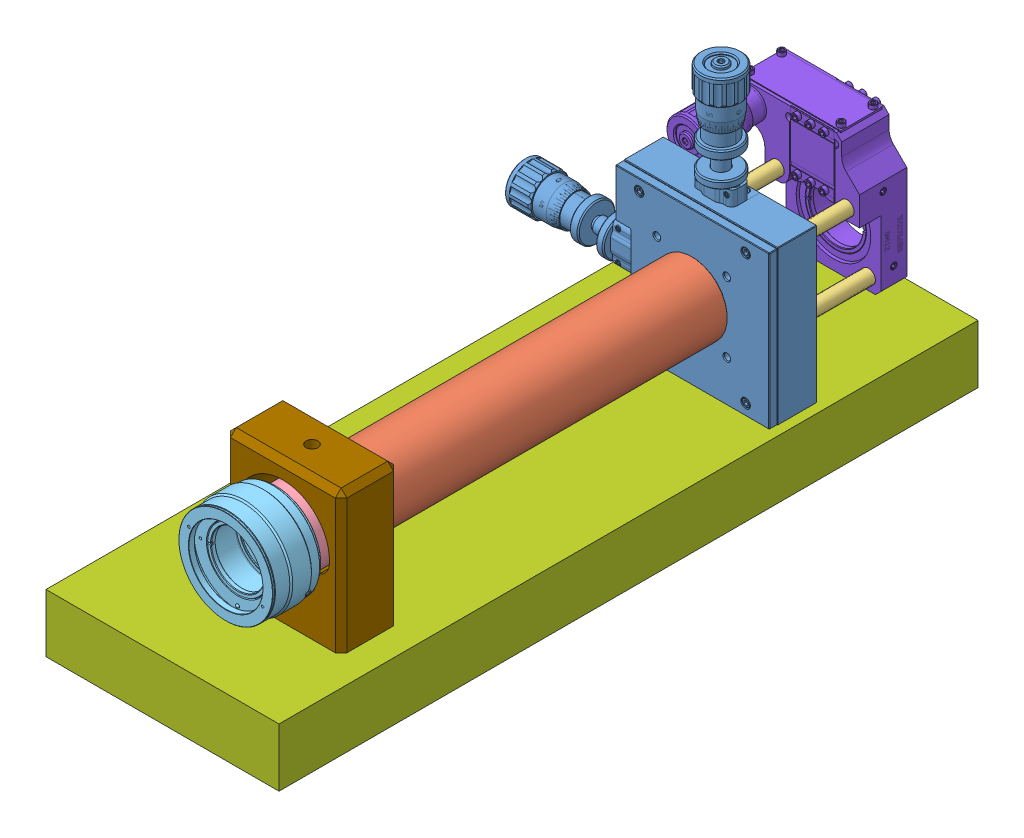
SolidWorks assembly telescope_assembly, configuration Default. Lengths in mm.
Overall size (116.48 139.66 300).
14 component instances, 10 part files, 17 mates.
Components (placement in the parent):
- ST1XY-D_pinhole_translation_stage-1: ST1XY-D_pinhole_translation_stage [Default] at (28.4444 18.502 77.2814) size (112.62 114.66 22.8)
- SM1E60_lens_tube_long-1: SM1E60_lens_tube_long [Default] at (61.4644 51.522 164.0224) x (-0.096761 0.995308 0) z (0 0 -1) size (30.48 30.48 155.45)
- ER2-P4_cage_rods-1: ER2-P4_cage_rods [Default] at (77.5245 65.4123 40.8865) x (0.999987 0.005042 0) z (0.005042 -0.999987 0) size (5.99 55.88 5.99)
- ER2-P4_cage_rods-2: ER2-P4_cage_rods [Default] at (77.5245 35.4123 40.8865) x (0.999987 0.005042 0) z (0.005042 -0.999987 0) size (5.99 55.88 5.99)
- ER2-P4_cage_rods-3: ER2-P4_cage_rods [Default] at (47.5245 65.4123 40.8865) x (0.999987 0.005042 0) z (0.005042 -0.999987 0) size (5.99 55.88 5.99)
- ER2-P4_cage_rods-4: ER2-P4_cage_rods [Default] at (47.5245 35.4123 40.8865) x (0.999987 0.005042 0) z (0.005042 -0.999987 0) size (5.99 55.88 5.99)
- SM1L10_lens_tue_extender-1: SM1L10_lens_tue_extender [Default] at (61.4644 51.522 267.9084) x (0 0 1) z (-0.974346 -0.225056 0) size (29.21 30.48 30.48)
- SM1ZM_lens_z_adjuster-1: SM1ZM_lens_z_adjuster [Default] at (61.4644 51.522 277.6874) size (41.66 41.66 25.27)
- P50S_50umpinhole-1: P50S_50umpinhole [Default] at (44.9788 60.0513 101.4906) x (0.923728 0.383049 0) z (0 0 -1) size (25.4 25.4 2.54)
- telescope_holder-1: telescope_holder [Default] at (48.3417 -6.498 153.6286) x (0 0 -1) z (1 0 0) size (300 25 100)
- SM1Z_cage_lens_z-2: SM1Z_cage_lens_z [Default] at (61.4529 51.5333 17.5964) x (-1 0 0) z (0 0 1) size (55.09 63.19 50.87)
- lens_tube_holder-1: lens_tube_holder [Default] at (6.623 23.6113 266.6126) x (0 0 -1) z (1 0 0) size (25 60 50)
  - lens_tube_holder-1: lens_tube_holder [Default] at (1.5123 12.0928 54.7947) size (25 60 50)
  - 90291A535_CONFORMABLE SOFT NYLON-TIP SET SCREW-2: 90291A535_CONFORMABLE SOFT NYLON-TIP SET SCREW [90291A535] at (14.0123 44.173 54.8414) x (0.752673 0 -0.658395) z (0 1 0) size (6.52 6.42 11.64)
Mates (geometry in assembly coordinates):
- Coincident1: coincident anti-aligned: plane of ST1XY-D_pinhole_translation_stage-1 through (28.4444 84.288 89.3464) normal (0 0 1); plane of SM1E60_lens_tube_long-1 through (61.4644 51.522 89.3464) normal (0 0 -1)
- Concentric1: concentric anti-aligned: circle of ST1XY-D_pinhole_translation_stage-1; circle of SM1E60_lens_tube_long-1
- Coincident2: coincident anti-aligned: plane of ST1XY-D_pinhole_translation_stage-1 through (28.4444 84.542 68.7724) normal (0 0 -1); plane of ER2-P4_cage_rods-1 through (76.4529 66.5334 68.7724) normal (0 0 1)
- Concentric2: concentric anti-aligned: circle of ST1XY-D_pinhole_translation_stage-1; circle of ER2-P4_cage_rods-1
- Concentric6: concentric anti-aligned: circle of SM1E60_lens_tube_long-1; circle of SM1L10_lens_tue_extender-1
- Coincident5: coincident anti-aligned: plane of SM1E60_lens_tube_long-1 through (61.4644 51.522 241.7464) normal (0 0 1); plane of SM1L10_lens_tue_extender-1 through (58.0345 66.371 241.7464) normal (0 0 -1)
- Concentric7: concentric aligned: circle of SM1L10_lens_tue_extender-1; circle of SM1ZM_lens_z_adjuster-1
- Coincident6: coincident anti-aligned: plane of SM1L10_lens_tue_extender-1 through (58.0345 66.371 267.9084) normal (0 0 1); plane of SM1ZM_lens_z_adjuster-1 through (80.5144 51.522 267.9084) normal (0 0 -1)
- Coincident7: coincident aligned: plane of ST1XY-D_pinhole_translation_stage-1 through (90.0183 46.1258 82.6701) normal (0 0 -1); plane of P50S_50umpinhole-1 through (66.3291 39.7906 82.6701) normal (0 0 -1)
- Concentric8: concentric aligned: circle of ST1XY-D_pinhole_translation_stage-1; circle of P50S_50umpinhole-1
- Parallel2: parallel anti-aligned: line of ST1XY-D_pinhole_translation_stage-1 through (94.4844 18.756 85.5364) axis (0 0 -1); line of telescope_holder-1 through (-1.6583 18.502 3.6286) axis (0 0 1)
- Coincident9: coincident anti-aligned: plane of ST1XY-D_pinhole_translation_stage-1 through (28.4444 18.502 85.7904) normal (0 -1 0); plane of telescope_holder-1 through (48.3417 18.502 153.6286) normal (0 1 0)
- Concentric13: concentric aligned: circle of ER2-P4_cage_rods-3; circle of SM1Z_cage_lens_z-2
- Concentric14: concentric aligned: circle of ER2-P4_cage_rods-2; circle of SM1Z_cage_lens_z-2
- Distance4: distance = 40 mm anti-aligned: plane of SM1Z_cage_lens_z-2 through (61.4529 51.5333 28.7724) normal (0 0 1); plane of ST1XY-D_pinhole_translation_stage-1 through (28.4444 84.542 68.7724) normal (0 0 -1)
- Concentric15: concentric anti-aligned: circle of SM1L10_lens_tue_extender-1; circle of lens_tube_holder-1/lens_tube_holder-1
- Coincident11: coincident anti-aligned: plane of telescope_holder-1 through (48.3417 18.502 153.6286) normal (0 1 0); plane of lens_tube_holder-1/lens_tube_holder-1 through (61.4178 18.502 240.1004) normal (0 -1 0)
